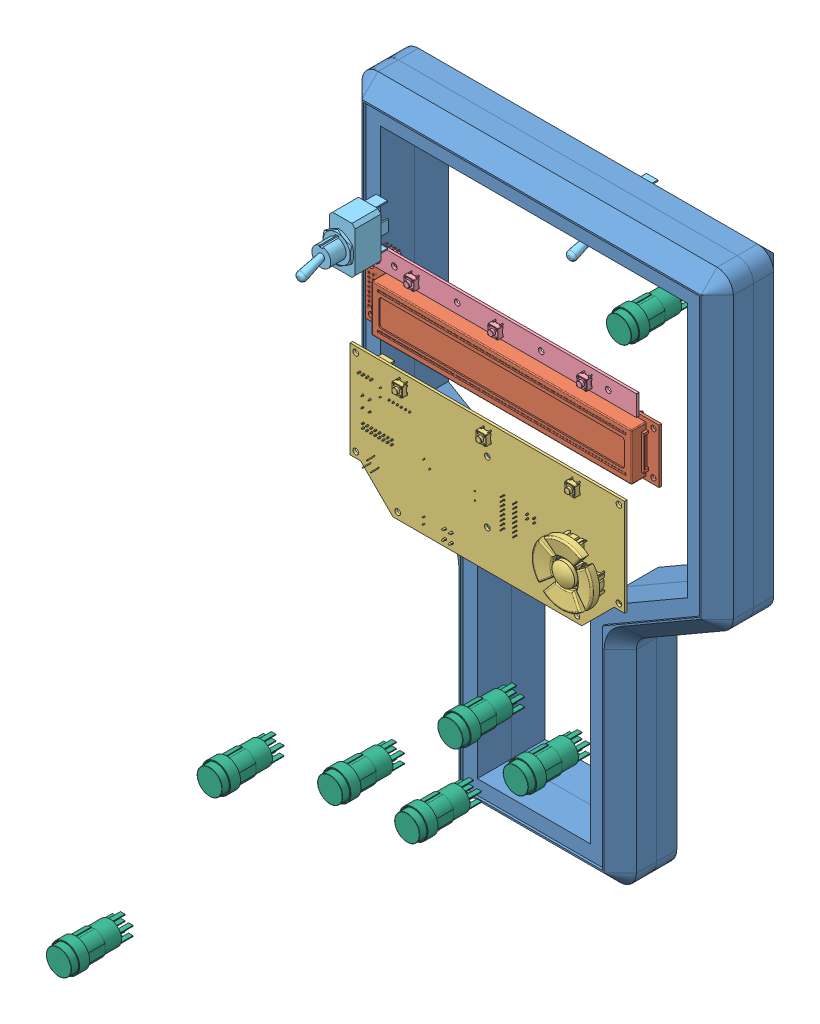
SolidWorks assembly Montagem 002, configuration Valor predeterminado. Lengths in mm.
Overall size (230 360 342.25).
15 component instances, 7 part files, 7 mates.
Components (placement in the parent):
- TEC02 - Moldura-1: TEC02 - Moldura [Valor predeterminado] at (3.3986 -156.1108 350.0592) size (230 360 22.5)
- TEC03 - Chapa-1: TEC03 - Chapa [Valor predeterminado] at (5.6362 17.2365 372.5592) x (-1 0 0) z (0 0 -1) size (208 338 1.5) (hidden)
- TEC02 - Moldura-2: TEC02 - Moldura [Valor predeterminado] at (3.3986 -156.1108 350.0592) x (-1 0 0) z (0 0 -1) size (230 360 22.5)
- LCD Display 4002-1: LCD Display 4002 [Valor predeterminado] at (4.4752 107.4389 381.0004) size (182 33.5 13.65)
- PCB_IHM-1: PCB_IHM [Valor predeterminado] at (-81.7461 26.8293 399.7352) size (170 80 27.35)
- Teclado_Superior-1: Teclado_Superior [Valor predeterminado] at (-81.7796 67.1807 392.3467) size (170.25 12.75 19.2)
- BCV3 112 103 - Controle chave geral-1: BCV3 112 103 - Controle chave geral [Default] at (-62.8496 160.752 415.4445) size (17 29 51.5)
- BCV3 112 102 - Controle botão-1: BCV3 112 102 - Controle botão [Valor predeterminado] at (2.451 -114.6413 371.0592) x (1 0 0) z (0 -1 0) size (17.7 39.7 17.7)
- BCV3 112 102 - Controle botão-2: BCV3 112 102 - Controle botão [Valor predeterminado] at (24.7165 -40.0946 508.2654) x (1 0 0) z (0 -1 0) size (17.7 39.7 17.7)
- BCV3 112 102 - Controle botão-3: BCV3 112 102 - Controle botão [Valor predeterminado] at (3.0158 -68.7474 412.1036) x (1 0 0) z (0 -1 0) size (17.7 39.7 17.7)
- BCV3 112 102 - Controle botão-4: BCV3 112 102 - Controle botão [Valor predeterminado] at (21.1636 -87.9751 456.9765) x (1 0 0) z (0 -1 0) size (17.7 39.7 17.7)
- BCV3 112 102 - Controle botão-5: BCV3 112 102 - Controle botão [Valor predeterminado] at (-15.6419 -39.0218 542.4955) x (1 0 0) z (0 -1 0) size (17.7 39.7 17.7)
- BCV3 112 102 - Controle botão-6: BCV3 112 102 - Controle botão [Valor predeterminado] at (-15.0956 -88.3282 636.4569) x (1 0 0) z (0 -1 0) size (17.7 39.7 17.7)
- BCV3 112 103 - Controle chave geral-3: BCV3 112 103 - Controle chave geral [Default] at (10.2452 161.2847 321.1033) size (17 29 51.5)
- BCV3 112 102 - Controle botão-7: BCV3 112 102 - Controle botão [Valor predeterminado] at (67.2959 159.9765 372.0092) x (1 0 0) z (0 -1 0) size (17.7 39.7 17.7)
Mates (geometry in assembly coordinates):
- Coincidente4: coincident anti-aligned: plane of TEC02 - Moldura-1 through (3.3986 -156.1108 350.0592) normal (0 0 -1); plane of TEC02 - Moldura-2 through (3.3986 -156.1108 350.0592) normal (0 0 1)
- Coincidente5: coincident aligned: plane of TEC02 - Moldura-1 through (118.3986 -156.1108 372.5592) normal (1 0 0); plane of TEC02 - Moldura-2 through (118.3986 -156.1108 327.5592) normal (1 0 0)
- Coincidente6: coincident aligned: plane of TEC02 - Moldura-1 through (3.3986 203.8892 372.5592) normal (0 1 0); plane of TEC02 - Moldura-2 through (3.3986 203.8892 327.5592) normal (0 1 0)
- Coincidente16: coincident anti-aligned: plane of TEC02 - Moldura-1 through (3.3986 -156.1108 371.0592) normal (0 0 1); plane of BCV3 112 102 - Controle botão-1 through (2.451 -114.6413 371.0592) normal (0 0 -1)
- Coincidente21: coincident anti-aligned: plane of TEC02 - Moldura-1 through (3.3986 -156.1108 371.0592) normal (0 0 1); plane of TEC03 - Chapa-1 through (5.6362 17.2365 371.0592) normal (0 0 -1)
- Coincidente22: coincident anti-aligned: plane of TEC02 - Moldura-1 through (-100.6014 192.8892 371.0592) normal (1 0 0); plane of TEC03 - Chapa-1 through (-100.6014 192.8892 371.0592) normal (-1 0 0)
- Coincidente23: coincident anti-aligned: plane of TEC02 - Moldura-1 through (107.3986 192.8892 371.0592) normal (0 -1 0); plane of TEC03 - Chapa-1 through (-100.6014 192.8892 371.0592) normal (0 1 0)
